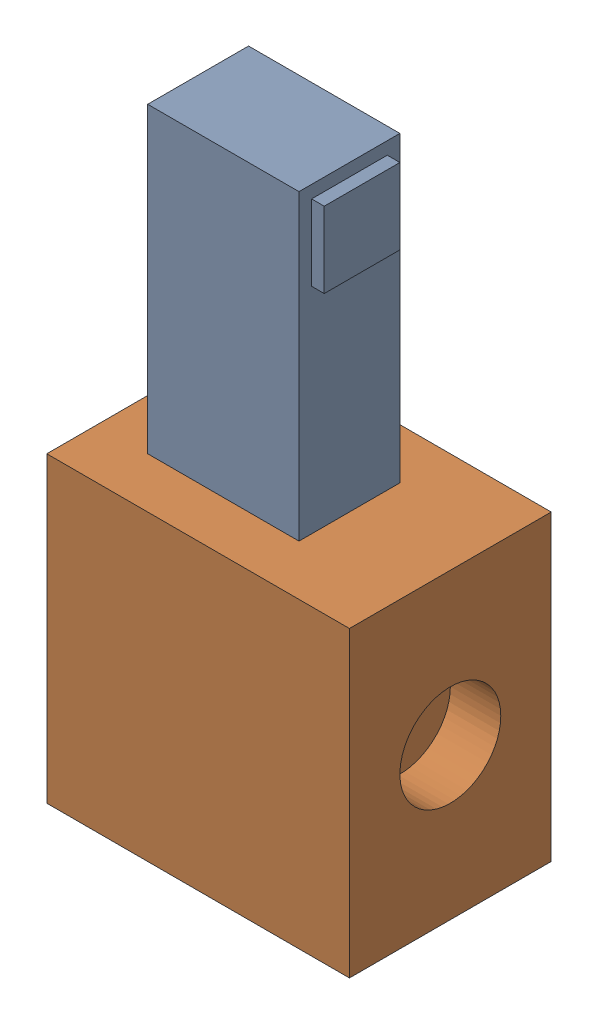
SolidWorks assembly Assem1, configuration Default. Lengths in mm.
Overall size (76.2 152.4 50.8).
2 component instances, 2 part files, 6 mates.
Components (placement in the parent):
- Part1-1: Part1 [Default] at (12.7 50.8 -12.7) size (41.27 101.6 25.4)
- Part2-1: Part2 [Default] at origin size (76.2 76.2 50.8)
Mates (geometry in assembly coordinates):
- Coincident1: coincident anti-aligned: plane of Part1-1 through (12.7 50.8 -12.7) normal (0 -1 0); plane of Part2-1 through (0 50.8 0) normal (0 1 0)
- Coincident2: coincident anti-aligned: plane of Part1-1 through (50.8 152.4 -12.7) normal (1 0 0); plane of Part2-1 through (50.8 50.8 -38.1) normal (-1 0 0)
- Coincident3: coincident anti-aligned: plane of Part1-1 through (12.7 152.4 -38.1) normal (0 0 -1); plane of Part2-1 through (12.7 50.8 -38.1) normal (0 0 1)
- Coincident4: coincident: point of Part2-1
- Coincident5: coincident anti-aligned: plane of Part2-1 through (0 0 0) normal (0 -1 0)
- Coincident6: coincident aligned: plane of Part2-1 through (0 76.2 0) normal (0 0 1)
